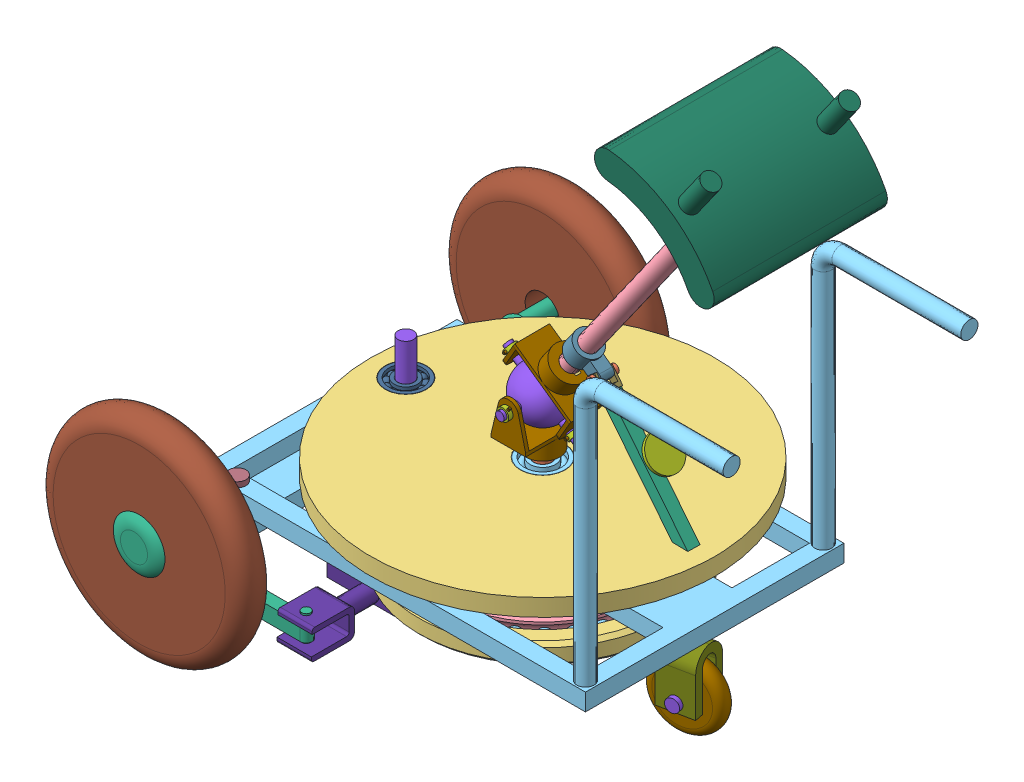
SolidWorks assembly P AND S, configuration Default. Lengths in mm.
Overall size (366.58 369.89 260.01).
99 component instances, 45 part files, 0 mates.
Components (placement in the parent):
- SUN ROD _1_-1: SUN ROD _1_ [Default] at origin size (10.05 70 11.26)
  - SUN ROD-1: SUN ROD [Default] at (0 0.2027 0) x (0.999987 0 0.005038) z (0 1 0) size (3 1.23 10)
  - Part 43-1: Part 43 [Default] at (0 0.2027 0) x (0.999987 0 0.005038) z (0 1 0) size (10 10 70)
- steering rod _1_-1: steering rod _1_ [Default] at origin size (124.18 169.5 12.46)
  - steering rod-1: steering rod [Default] at (10.4376 102.8659 0.2205) x (0.814687 -0.5799 -0.001045) z (0.006253 0.010586 -0.999924) size (1.23 10 3)
  - Part 45-1: Part 45 [Default] at (10.4376 102.8659 0.2205) x (0.814687 -0.5799 -0.001045) z (0.006253 0.010586 -0.999924) size (10 200 10)
- ball-1: ball [Default] at (58.9284 6.2117 8.5818) x (0 1 0) z (0.989562 0 0.144111) size (8.9 8.9 8.9)
- ball-2: ball [Default] at (42.6298 6.2117 41.5801) x (0 1 0) z (0.715866 0 0.698238) size (8.9 8.9 8.9)
- ball-3: ball [Default] at (-22.0321 6.2117 -55.3244) x (0 1 0) z (-0.369977 0 -0.929041) size (8.9 8.9 8.9)
- ball-4: ball [Default] at (22.0321 6.2117 55.3244) x (0 1 0) z (0.369977 0 0.929041) size (8.9 8.9 8.9)
- ball-5: ball [Default] at (52.7183 6.2117 -27.6944) x (0 1 0) z (0.885278 0 -0.465062) size (8.9 8.9 8.9)
- ball-6: ball [Default] at (-42.6298 6.2117 -41.5801) x (0 1 0) z (-0.715866 0 -0.698238) size (8.9 8.9 8.9)
- ball-7: ball [Default] at (-50.3432 6.2117 -31.8082) x (0 1 0) z (-0.845394 0 -0.534143) size (8.9 8.9 8.9)
- ball-8: ball [Default] at (-2.3751 6.2117 59.5026) x (0 1 0) z (-0.039884 0 0.999204) size (8.9 8.9 8.9)
- ball-9: ball [Default] at (-57.3243 6.2117 16.1285) x (0 1 0) z (-0.962625 0 0.270839) size (8.9 8.9 8.9)
- ball-10: ball [Default] at (-52.7183 6.2117 27.6944) x (0 1 0) z (-0.885278 0 0.465062) size (8.9 8.9 8.9)
- ball-11: ball [Default] at (10.0481 6.2117 58.6961) x (0 1 0) z (0.168734 0 0.985662) size (8.9 8.9 8.9)
- ball-12: ball [Default] at (2.3751 6.2117 -59.5026) x (0 1 0) z (0.039884 0 -0.999204) size (8.9 8.9 8.9)
- ball-13: ball [Default] at (33.0533 6.2117 49.5347) x (0 1 0) z (0.555051 0 0.831816) size (8.9 8.9 8.9)
- ball-14: ball [Default] at (50.3432 6.2117 31.8082) x (0 1 0) z (0.845394 0 0.534143) size (8.9 8.9 8.9)
- ball-15: ball [Default] at (55.8564 6.2117 20.6462) x (0 1 0) z (0.937975 0 0.346703) size (8.9 8.9 8.9)
- ball-16: ball [Default] at (-26.3716 6.2117 53.3923) x (0 1 0) z (-0.442849 0 0.896596) size (8.9 8.9 8.9)
- ball-17: ball [Default] at (-33.0533 6.2117 -49.5347) x (0 1 0) z (-0.555051 0 -0.831816) size (8.9 8.9 8.9)
- ball-18: ball [Default] at (-45.8083 6.2117 38.05) x (0 1 0) z (-0.769241 0 0.638959) size (8.9 8.9 8.9)
- ball-19: ball [Default] at (-59.4249 6.2117 3.8576) x (0 1 0) z (-0.9979 0 0.06478) size (8.9 8.9 8.9)
- ball-20: ball [Default] at (57.3243 6.2117 -16.1285) x (0 1 0) z (0.962625 0 -0.270839) size (8.9 8.9 8.9)
- ball-21: ball [Default] at (36.8962 6.2117 -46.7426) x (0 1 0) z (0.619584 0 -0.78493) size (8.9 8.9 8.9)
- ball-22: ball [Default] at (-10.0481 6.2117 -58.6961) x (0 1 0) z (-0.168734 0 -0.985662) size (8.9 8.9 8.9)
- ball-23: ball [Default] at (59.4249 6.2117 -3.8576) x (0 1 0) z (0.9979 0 -0.06478) size (8.9 8.9 8.9)
- ball-24: ball [Default] at (-55.8564 6.2117 -20.6462) x (0 1 0) z (-0.937975 0 -0.346703) size (8.9 8.9 8.9)
- ball-25: ball [Default] at (-58.9284 6.2117 -8.5818) x (0 1 0) z (-0.989562 0 -0.144111) size (8.9 8.9 8.9)
- ball-26: ball [Default] at (45.8083 6.2117 -38.05) x (0 1 0) z (0.769241 0 -0.638959) size (8.9 8.9 8.9)
- ball-27: ball [Default] at (26.3716 6.2117 -53.3923) x (0 1 0) z (0.442849 0 -0.896596) size (8.9 8.9 8.9)
- ball-28: ball [Default] at (-14.6945 6.2117 57.7085) x (0 1 0) z (-0.246759 0 0.969077) size (8.9 8.9 8.9)
- ball-29: ball [Default] at (14.6945 6.2117 -57.7085) x (0 1 0) z (0.246759 0 -0.969077) size (8.9 8.9 8.9)
- ball-30: ball [Default] at (-36.8962 6.2117 46.7426) x (0 1 0) z (-0.619584 0 0.78493) size (8.9 8.9 8.9)
- Part1-1: Part1 [Default] at (-107.5957 20.916 89.8855) x (0 -1 0) z (1 0 0.000187) size (30 40 30)
- Part1-2: Part1 [Default] at (-107.4041 20.7981 -90.1144) x (0 1 0) z (1 0 0.000187) size (30 40 30)
- ujoint bush-1: ujoint bush [Default] at (0.0299 88.2027 23.3) x (0.5799 0.814687 -0.000744) z (-0.001282 0 -0.999999) size (7 7 2.5)
- ujoint bush-2: ujoint bush [Default] at (18.9822 74.6911 -0.0243) x (0.001282 0 0.999999) z (-0.814687 0.5799 0.001045) size (7 7 2.5)
- ujoint bush-3: ujoint bush [Default] at (-18.9822 101.7144 0.0243) x (-0.001282 0 -0.999999) z (0.814687 -0.5799 -0.001045) size (7 7 2.5)
- ujoint bush-4: ujoint bush [Default] at (-0.0265 88.2027 -20.7) x (0.5799 0.814687 -0.000744) z (-0.001282 0 -0.999999) size (7 7 2.5)
- Part5-1: Part5 [Default] at (83.0384 -20.0491 -9.7153) x (0 -1 0) z (0.980573 0 -0.196154) size (7.5 25 7.5)
- u-joint jock-1: u-joint jock [Default] at (0 72.2027 0) x (-0.001282 0 -0.999999) z (0.999999 0 -0.001282) size (40 33.98 20)
- u-joint jock-2: u-joint jock [Default] at (9.2779 101.2366 0.196) x (0.814687 -0.5799 -0.001045) z (0.006253 0.010586 -0.999924) size (40 33.98 20)
- carrier-1: carrier [Default] at (0 -2.7973 0) x (-0.592672 0 0.805444) z (0.805444 0 0.592672) size (65 15 5)
- spur gear_am-1: spur gear_am [Default] at (59.0424 82.7006 -3.1152) x (0.767162 0.641249 0.016208) z (-0.272517 0.348693 -0.896743) size (5 8.47 8.43)
- LA ROD-1: LA ROD [Default] at (58.6949 86.905 1.24) x (-0.641106 0.767333 -0.013544) z (-0.021122 0 0.999777) size (38.5 5 10)
- nut-1: nut [Default] at (-107.4254 24.4509 -70.1144) x (0.670947 0 0.741505) z (-0.741505 0 0.670947) size (10 26 10)
- nut-2: nut [Default] at (-107.5744 24.4509 69.8855) size (10 26 10)
- nut-3: nut [Default] at (-107.4999 24.4509 -0.1144) size (10 26 10)
- steering joint-1: steering joint [Default] at (27.3159 126.5771 0.5771) x (0.814437 -0.579997 0.017206) z (-0.021122 0 0.999777) size (23.75 10 15)
- instrument ball bearing_68_am-1: instrument ball bearing_68_am [Default] at (85 17.4509 0.0905) x (0 1 0) z (0.002576 0 0.999997) size (6 20 20)
- instrument ball bearing_68_am-2: instrument ball bearing_68_am [Default] at (-107.5957 11.4509 89.8855) x (0 -1 0) z (0.001064 0 -0.999999) size (6 20 20)
- instrument ball bearing_68_am-3: instrument ball bearing_68_am [Default] at (-107.3978 20.7981 -124.1144) x (0.000187 0 -1) z (0.998035 -0.062662 0.000186) size (6 20 20)
- instrument ball bearing_68_am-4: instrument ball bearing_68_am [Default] at (-107.6021 20.916 123.8855) x (0.000187 0 -1) z (-0.426798 0.904347 -0.00008) size (6 20 20)
- instrument ball bearing_68_am-5: instrument ball bearing_68_am [Default] at (-107.4041 11.4509 -90.1144) x (0 -1 0) z (0.001064 0 -0.999999) size (6 20 20)
- Part3-1: Part3 [Default] at (85 20.4509 0.0905) x (0.196154 0 0.980573) z (-0.980573 0 0.196154) size (20 45.5 20)
- end_joint-1: end_joint [Default] at (-47.2421 -10 -84.3624) x (-0.001064 0 0.999999) z (0 1 0) size (52 49 17)
- end_joint-2: end_joint [Default] at (-47.4218 -10 84.3849) x (0.001064 0 -0.999999) z (0 1 0) size (52 49 17)
- spur gear_am-1-1: spur gear_am-1 [Default] at (0 12.2027 0) x (0 -1 0) z (-0.001862 0 -0.999998) size (12 43.61 43.61)
- aa-1: aa [Default] at (23.9276 -4.7883 -0.1801) x (-1 0 0.000579) z (0.000579 0 1) size (45 5 5)
- aa-2: aa [Default] at (-23.8821 -4.7883 -0.1524) x (1 0 -0.000579) z (-0.000579 0 -1) size (45 5 5)
- LA PIN-1: LA PIN [Default] at (35.7629 114.529 -6.246) x (0.128637 0.991688 0.002718) z (-0.991467 0.128666 -0.020946) size (5 14 5)
- turntable-1: turntable [Default] at (0 55.2027 0) x (0.999995 0 0.003102) z (-0.003102 0 0.999995) size (200 10 200)
- l bracket-1: l bracket [Default] at (62.05 12 2.4122) x (-1 0 0) z (0 1 0) size (27.85 5 17)
- l bracket-2: l bracket [Default] at (-2.4734 12 61.9886) x (0 0 -1) z (0 1 0) size (27.85 5 17)
- l bracket-3: l bracket [Default] at (-61.9602 12 -2.6269) x (1 0 0) z (0 1 0) size (27.85 5 17)
- l bracket-4: l bracket [Default] at (2.7362 12 -62.0315) x (0 0 1) z (0 1 0) size (27.85 5 17)
- radial ball bearing_68_am-1: radial ball bearing_68_am [Default] at (0 50.2027 0) x (0 1 0) z (0.999996 0 0.002704) size (10 26 26)
- tyrerod-1: tyrerod [Default] at (-76.4271 -10.0859 86.5058) x (1 0 0.000187) z (0 1 0) size (68.17 9 45)
- tyrerod-2: tyrerod [Default] at (-76.2355 -10.0859 -93.4941) x (1 0 0.000187) z (0 1 0) size (68.17 9 45)
- la spur rod-1: la spur rod [Default] at (66.714 89.1131 -2.9531) x (-0.484609 0.562841 0.6696) z (-0.420258 0.521546 -0.742545) size (20 12 20)
- ujoint cross1-1: ujoint cross1 [Default] at (0 88.2027 0) x (-0.814687 0.5799 0.001045) z (-0.001282 0 -0.999999) size (50 30 50)
- ujoint pin-1: ujoint pin [Default] at (-0.0282 88.2027 -22) x (0.518723 -0.369934 -0.770763) z (-0.5799 -0.814687 0.000744) size (1.5 1.5 10)
- ujoint pin-2: ujoint pin [Default] at (-17.9231 100.9605 0.023) x (-0.647422 0.762131 0.00083) z (-0.001282 0 -0.999999) size (1.5 1.5 10)
- ujoint pin-3: ujoint pin [Default] at (17.9231 75.4449 -0.023) x (-0.996245 0.086567 0.001277) z (-0.001282 0 -0.999999) size (1.5 1.5 10)
- ujoint pin-4: ujoint pin [Default] at (0.0282 88.2027 22) x (0.44788 -0.318041 0.835616) z (-0.5799 -0.814687 0.000744) size (1.5 1.5 10)
- instrument ball bearing_68_am-1-1: instrument ball bearing_68_am-1 [Default] at (-79.7996 51.7027 -0.2475) x (0 -1 0) z (-0.463117 0 0.886297) size (7 24 24)
- instrument ball bearing_68_am-1-2: instrument ball bearing_68_am-1 [Default] at (0 20.9509 0) x (0 -1 0) z (-0.13935 0 0.990243) size (7 24 24)
- tyre-1: tyre [Default] at (-107.6026 20.916 126.8855) x (0.426798 -0.904347 0.00008) z (-0.904347 -0.426798 -0.000169) size (120 20 120)
- tyre-2: tyre [Default] at (-107.401 20.7981 -107.1144) x (0.998035 -0.062662 0.000186) z (-0.062662 -0.998035 -0.000012) size (120 20 120)
- instrument ball bearing_68_am-2-1: instrument ball bearing_68_am-2 [Default] at (0 36.31 0) x (0 1 0) z (0 0 1) size (4.5 15 15)
- _rack spur rectangular_am_-_TeethCuts_-1: _rack spur rectangular_am_-_TeethCuts_ [Default] at (79.7146 40.3077 16.926) x (0.641106 -0.767333 0.013544) z (0.021122 0 -0.999777) size (35 5 3.5)
- spur gear_am-2-1: spur gear_am-2 [Default] at (0 28.56 0) x (0 1 0) z (0 0 1) size (10 123.89 123.89)
- cushion-1: cushion [Default] at (118.0288 254.0975 -47.5093) x (0.814686 -0.579901 -0.00097) z (0.579868 0.814619 0.012251) size (81.02 100 46.92)
- spur gear_am-3-1: spur gear_am-3 [Default] at (0 -14.7883 0) x (0 1 0) z (-0.700984 0 -0.713177) size (10 80 79.7)
- bb-1: bb [Default] at (0 -4.7883 0) x (0.677205 0 -0.735795) z (0.735795 0 0.677205) size (10 10 10)
- spur gear_am-4-1: spur gear_am-4 [Default] at (17.7801 0.2027 -24.1633) x (0 1 0) z (0.997401 0 0.072044) size (12 24 22.98)
- spur gear_am-4-2: spur gear_am-4 [Default] at (-17.7801 0.2027 24.1633) x (0 1 0) z (0.380482 0 -0.924789) size (12 24 22.98)
- rack spur rectangular_am-1: rack spur rectangular_am [Default] at (-57.3905 -15 45.0006) x (0.001064 0 -0.999999) z (0.999999 0 0.001064) size (90 10 22.5)
- spur gear_am-5-1: spur gear_am-5 [Default] at (-79.7996 28.56 -0.2475) x (0 1 0) z (0.680073 0 0.733145) size (10 43.61 43.61)
- outer-1: outer [Default] at (0 6.2117 0) x (0 1 0) z (-0.638025 0 0.770016) size (12 144 144)
- inner-1: inner [Default] at (0 6.2117 0) x (0 1 0) z (0.769241 0 -0.638959) size (12 113.19 113.19)
- frame-1: frame [Default] at (-50 14.4509 -0.0532) x (0.999999 0 0.001064) z (0.001064 0 -0.999999) size (304 175 210)
- LA COVER-1: LA COVER [Default] at (59.1448 80.9084 1.2495) x (-0.641106 0.767333 -0.013544) z (0.767162 0.641249 0.016208) size (72.85 13.75 7)
- internal spur gear_am-1: internal spur gear_am [Default] at (0 0.2117 0) x (0 1 0) z (0.874869 0 0.484359) size (12 85.05 85.05)
- 10mmrod-1: 10mmrod [Default] at (-79.7996 56.56 -0.2475) x (0.810244 0 0.586093) z (-0.586093 0 0.810244) size (9 48 9)
- Part2-1: Part2 [Default] at (84.0192 -20.0491 -4.8124) x (0.511861 0.852944 -0.102393) z (-0.836374 0.522002 0.167308) size (40 10 40)
